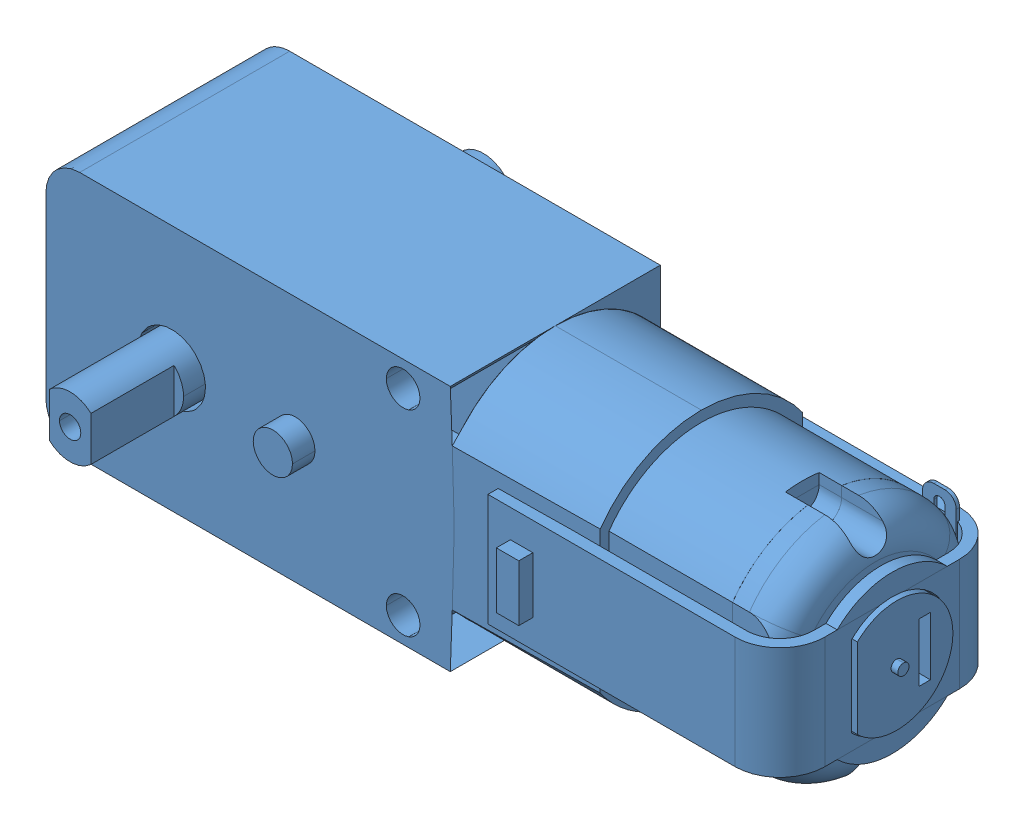
SolidWorks assembly Wheel_plus_motor, configuration Default. Lengths in mm.
Overall size (72.01 26.37 41.02).
3 component instances, 3 part files, 5 mates.
Components (placement in the parent):
- Wheel D65x25.step-1: Wheel D65x25.step [Default] at (-0.4541 43.5612 76.6912) size (69.02 69.02 30) (hidden)
- yellow_toy_motor_dims-1: yellow_toy_motor_dims [Default] at (-12.3027 43.4626 37.3412) size (72.01 26.37 41.02)
- encoder20p-1: encoder20p [Predeterminado] at (-1.1027 43.4626 19.9412) size (25.6 25.6 3.5) (hidden)
Mates (geometry in assembly coordinates):
- Tangent1: tangent anti-aligned: plane of Wheel D65x25.step-1 through (-0.4541 43.5612 46.6912) normal (0 0 -1); face of yellow_toy_motor_dims-1
- Lock1: lock: unknown of Wheel D65x25.step-1; unknown of yellow_toy_motor_dims-1
- Tangent3: tangent: plane of assembly; face of yellow_toy_motor_dims-1; plane of encoder20p-1 through (-1.1027 43.4626 18.9412) normal (0 0 -1)
- Tangent4: tangent: plane of assembly; face of yellow_toy_motor_dims-1; plane of encoder20p-1 through (-2.9527 41.496 22.4412) normal (1 0 0)
- Tangent5: tangent: cylinder of assembly; face of yellow_toy_motor_dims-1; cylinder of encoder20p-1 through (-1.1027 43.4626 22.4412) axis (0 0 -1) radius 2.7
